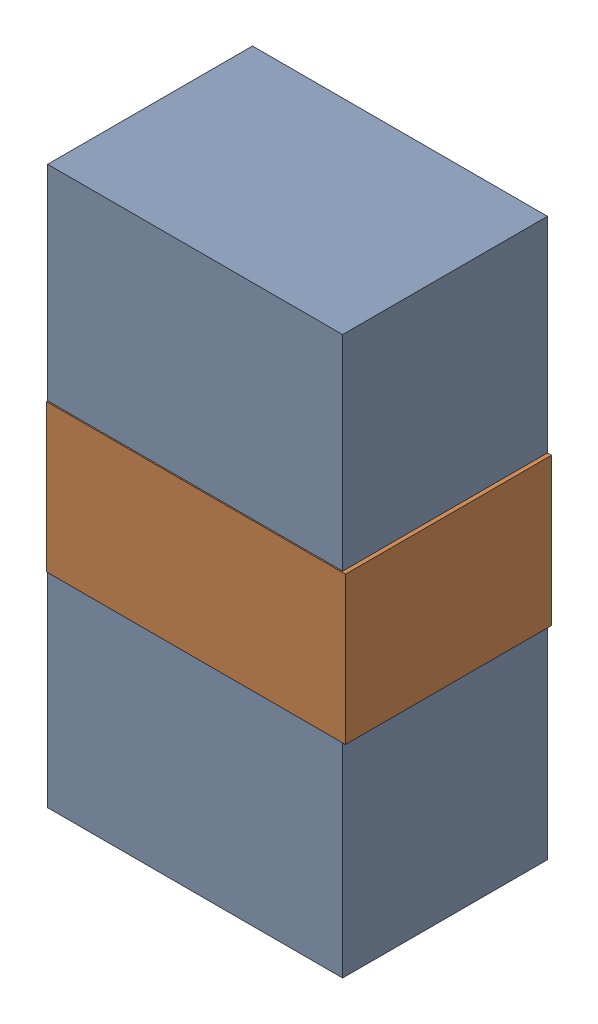
SolidWorks assembly LED2_Motor_2Kanaloa_v2.0.0_Motor, configuration Default. Lengths in mm.
Overall size (1.83 3.4 1.26).
4 component instances, 2 part files, 0 mates.
Components (placement in the parent):
- 334788016-1: 334788016 [Default] at (127.7495 63.754 0) size (1.8 3.4 1.25)
  - Extruded_12-1: Extruded_12 [Default] at origin size (1.8 3.4 1.25)
- 334787760-1: 334787760 [Default] at (127.762 63.754 0) size (1.83 0.9 1.26)
  - Extruded_13-1: Extruded_13 [Default] at origin size (1.83 0.9 1.26)
